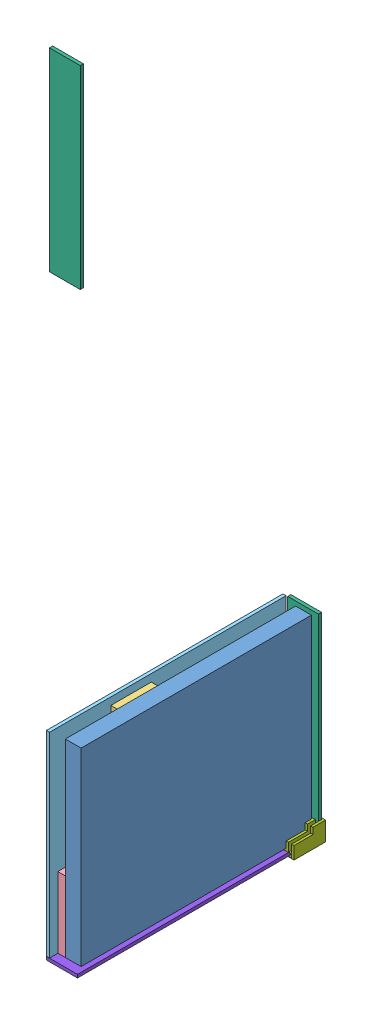
SolidWorks assembly ecran, configuration Défaut. Lengths in mm.
Overall size (122.3 1322.46 451.17).
9 component instances, 8 part files, 27 mates.
Components (placement in the parent):
- ecran-2: ecran [Défaut] at (-25 -947.5551 0) x (0 0 -1) z (1 0 0) size (365 300 25)
- carte aumage-3: carte aumage [Défaut] at (-25 -909.7551 60.4325) x (0 0 -1) z (-1 0 0) size (93 37.8 8)
- carte retro eclerage-3: carte retro eclerage [Défaut] at (-25 -802.5551 218.8676) x (0 -1 0) z (-1 0 0) size (155 64 10)
- carte video-3: carte video [Défaut] at (-37 -947.5551 240.5) x (0 0 -1) z (1 0 0) size (124.5 112 12)
- vitre-3: vitre [Défaut] at (-45 -950.8051 0) x (0 0 -1) z (1 0 0) size (375 310 5)
- vitre cot-1: vitre cot [Défaut] at (51.9579 344.0373 436.1698) size (48.75 307.5 5)
- attache-1: attache [Défaut] at (12.5 -975.8945 28.7613) x (-1 0 0) z (0 1 0) size (60 50 30)
- vitre cot-2: vitre cot [Défaut] at (-14.0875 -663.9239 -7.5) size (48.75 307.5 5)
- vitre haut bas-1: vitre haut bas [Défaut] at (-122.8096 -956.5664 196.7706) x (0 0 1) z (0 1 0) size (382.5 48.75 5)
Mates (geometry in assembly coordinates):
- Coïncidente4: coincident anti-aligned: plane of ecran-2 through (-25 -947.5551 0) normal (-1 0 0); plane of carte video-3 through (-25 -947.5551 240.5) normal (1 0 0)
- Coïncidente5: coincident aligned: line of ecran-2 through (-25 -947.5551 365) axis (0 0 -1); line of carte video-3 through (-25 -947.5551 365) axis (0 0 -1)
- Coïncidente6: coincident aligned: line of ecran-2 through (-25 -647.5551 365) axis (0 -1 0); line of carte video-3 through (-25 -835.5551 365) axis (0 -1 0)
- Coïncidente7: coincident anti-aligned: plane of ecran-2 through (-25 -947.5551 0) normal (-1 0 0); plane of carte retro eclerage-3 through (-25 -802.5551 218.8676) normal (1 0 0)
- Coïncidente8: coincident anti-aligned: line of ecran-2 through (-25 -647.5551 0) axis (0 0 1); line of carte retro eclerage-3 through (-25 -647.5551 282.8676) axis (0 0 -1)
- Parallèle1: parallel aligned: line of vitre-2 through (0 -640.8051 362.6575) axis (0 -1 0); line of vitre-3 through (-40 -640.8051 375) axis (0 -1 0)
- Parallèle2: parallel aligned: line of vitre-2 through (0 -950.8051 -12.3425) axis (0 1 0); line of vitre-3 through (-40 -950.8051 0) axis (0 1 0)
- Parallèle3: parallel aligned: line of vitre-2 through (0 -950.8051 362.6575) axis (0 0 -1); line of vitre-3 through (-40 -950.8051 375) axis (0 0 -1)
- Parallèle4: parallel aligned: line of vitre-2 through (0 -640.8051 -12.3425) axis (0 0 1); line of vitre-3 through (-40 -640.8051 0) axis (0 0 1)
- Coïncidente16: coincident aligned: plane of ecran-2 through (0 -947.5551 0) normal (1 0 0)
- Coïncidente17: coincident anti-aligned: plane of ecran-2 through (0 -947.5551 0) normal (0 0 -1)
- Parallèle5: parallel aligned: line of vitre-2 through (0 -950.8051 -12.3425) axis (0 1 0); line of vitre-3 through (-40 -950.8051 0) axis (0 1 0)
- Parallèle6: parallel anti-aligned: plane of vitre-2 through (0 -950.8051 -12.3425) normal (-1 0 0); plane of vitre-3 through (-40 -950.8051 0) normal (1 0 0)
- Coïncidente22: coincident anti-aligned: plane of ecran-2 through (-25 -947.5551 0) normal (-1 0 0); plane of carte aumage-3 through (-25 -909.7551 60.4325) normal (1 0 0)
- Coïncidente23: coincident anti-aligned: line of ecran-2 through (-25 -947.5551 365) axis (0 0 -1); line of carte aumage-3 through (-25 -947.5551 60.4325) axis (0 0 1)
- Coïncidente24: coincident anti-aligned: plane of ecran-2 through (0 -947.5551 0) normal (0 -1 0); plane of attache-1 through (12.5 -947.5551 28.7613) normal (0 1 0)
- Coïncidente25: coincident anti-aligned: plane of ecran-2 through (0 -947.5551 0) normal (0 0 -1); plane of attache-1 through (12.5 -948.0551 0) normal (0 0 1)
- Coïncidente26: coincident anti-aligned: plane of ecran-2 through (-25 -947.5551 0) normal (-1 0 0); plane of attache-1 through (-25 -947.5551 28.7613) normal (1 0 0)
- Coïncidente34: coincident anti-aligned: plane of vitre-3 through (-45 -950.8051 0) normal (-1 0 0); plane of attache-1 through (-45 -975.8945 0) normal (1 0 0)
- Coïncidente35: coincident anti-aligned: plane of attache-1 through (8.75 -947.5551 28.7613) normal (-1 0 0); plane of vitre cot-2 through (8.75 -643.0551 -2.5) normal (1 0 0)
- Coïncidente36: coincident anti-aligned: plane of attache-1 through (12.5 -955.0551 -2.5) normal (0 0 -1); plane of vitre cot-2 through (-14.0875 -663.9239 -2.5) normal (0 0 1)
- Coïncidente37: coincident anti-aligned: plane of attache-1 through (-45 -951.5664 -8) normal (0 -1 0); plane of vitre haut bas-1 through (-122.8096 -951.5664 196.7706) normal (0 1 0)
- Coïncidente38: coincident anti-aligned: plane of attache-1 through (-45 -951.5664 -8) normal (1 0 0); plane of vitre haut bas-1 through (-45 -951.5664 -8) normal (-1 0 0)
- Coïncidente39: coincident anti-aligned: plane of attache-1 through (12.5 -975.8945 -8) normal (0 0 1); plane of vitre haut bas-1 through (3.75 -951.5664 -8) normal (0 0 -1)
- Coïncidente40: coincident anti-aligned: plane of vitre-3 through (-40 -950.8051 0) normal (0 -1 0); plane of attache-1 through (12.5 -950.8051 28.7613) normal (0 1 0)
- Coïncidente41: coincident anti-aligned: plane of vitre-2 through (5 -950.8051 -12.3425) normal (0 -1 0); plane of attache-1 through (-40 -950.8051 -10) normal (0 1 0)
- Coïncidente44: coincident anti-aligned: plane of attache-1 through (12.5 -950.5551 28.7613) normal (0 1 0); plane of vitre cot-2 through (-40 -950.5551 -2.5) normal (0 -1 0)
